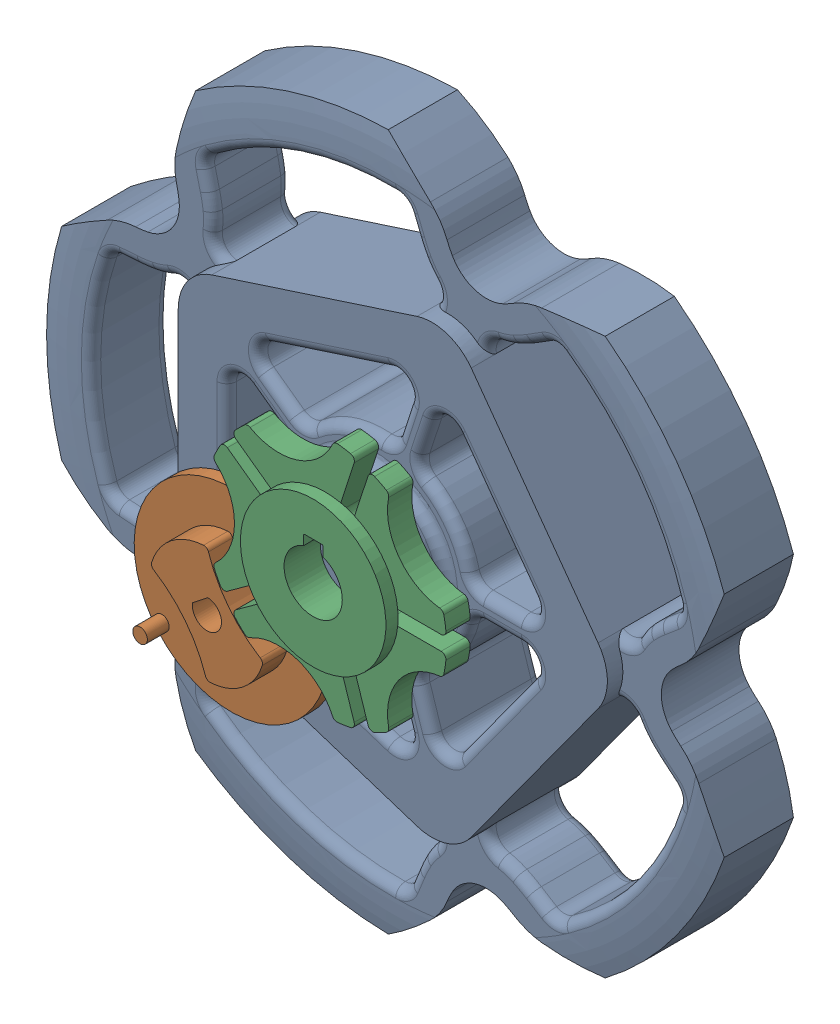
SolidWorks assembly SprocketsandGenevaMechanism, configuration Default. Lengths in mm.
Overall size (139.7 143.63 35.2).
4 component instances, 3 part files, 3 mates.
Components (placement in the parent):
- Sprocket1-1: Sprocket1 [Default] at (38.9197 -23.3765 42.0366) size (139.7 143.63 25.2)
- GenevaWheelMechanism-1: GenevaWheelMechanism [Default] at (38.9197 -23.3765 66.0366) x (-0.789564 -0.613668 0) z (0 0 -1) size (85.9 68.64 10)
  - GenevaDriveWheel-1: GenevaDriveWheel [Default] at (50.514 -1.048 7.5) x (-0.999987 0.005075 0) z (0 0 -1) size (40 40 7.5)
  - GenevaWheel-1: GenevaWheel [Default] at (0 0 2.5) x (0.789564 0.613668 0) z (0 0 1) size (47.83 49.76 7.5)
Mates (geometry in assembly coordinates):
- Concentric1: concentric anti-aligned: cylinder of Sprocket1-1 through (38.9197 -23.3765 30.8366) axis (0 0 1) radius 6; cylinder of GenevaWheelMechanism-1/GenevaWheel-1 through (38.9197 -23.3765 66.0366) axis (0 0 -1) radius 6
- Coincident1: coincident aligned: plane of Sprocket1-1 through (36.9197 -15.5765 30.8366) normal (0 -1 0); plane of GenevaWheelMechanism-1/GenevaWheel-1 through (40.9197 -15.5765 66.0366) normal (0 -1 0)
- Coincident2: coincident anti-aligned: plane of Sprocket1-1 through (38.9197 -23.3765 56.0366) normal (0 0 1); plane of GenevaWheelMechanism-1/GenevaDriveWheel-1 through (14.5222 -42.3388 56.0366) normal (0 0 -1)
